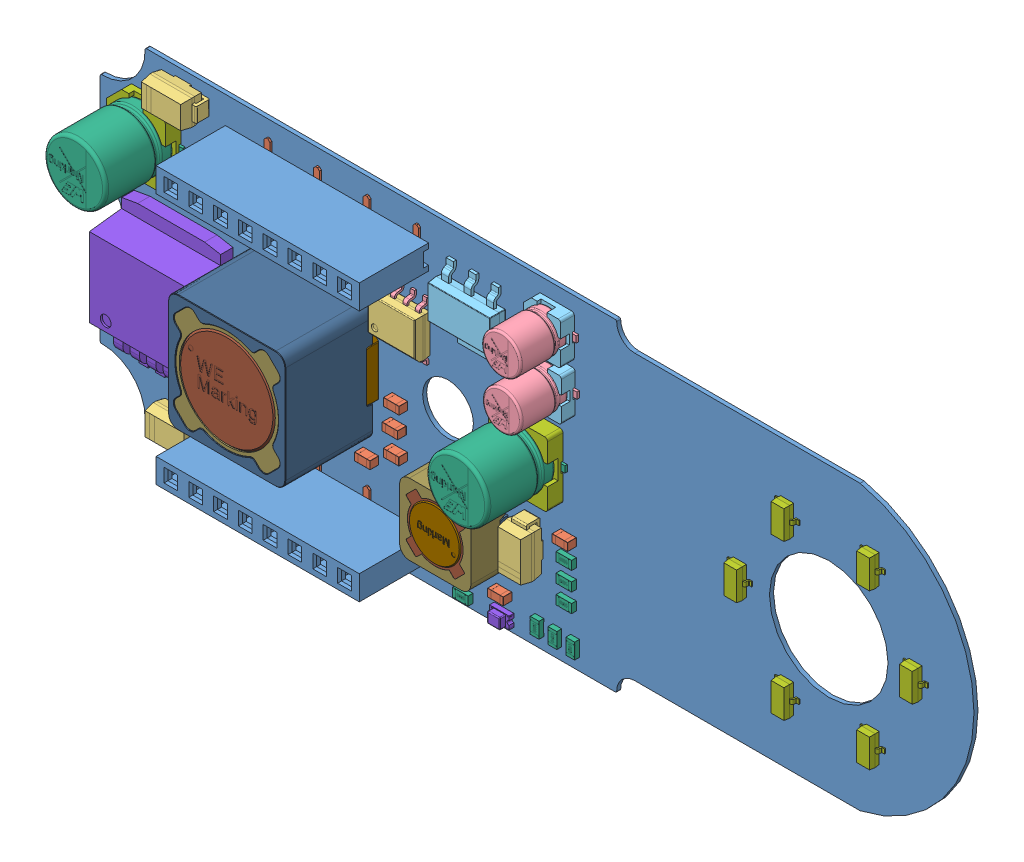
SolidWorks assembly magic_arm_1_PCB_18_9, configuration Default. Lengths in mm.
Overall size (89.5 33.05 10.11).
125 component instances, 33 part files, 0 mates.
Components (placement in the parent):
- Board-1: Board [Default] at (0 0 -0.4115) size (89.5 33.05 0.41)
- C13-1: C13 [Default] at origin size (1.6 0.8 0.9)
  - User_Library-CAPC1608X09-1: User_Library-CAPC1608X09 [Default] at (47.849 11.1761 0) x (1 0 0) z (0 0 1) size (1.6 0.8 0.9)
- IC1-1: IC1 [Default] at origin size (5 6.01 1.75)
  - User_Library-SOIC-8-1: User_Library-SOIC-8 [Default] at (31.4305 22.4028 0) x (1 0 0) z (0 -1 0) size (5 1.75 6.01)
    - User_Library-SOIC-8_SOIC-8_Body_1-1: User_Library-SOIC-8_SOIC-8_Body_1 [Default] at origin size (5 1.6 4)
    - User_Library-SOIC-8_SOIC-8_Pins_1-1: User_Library-SOIC-8_SOIC-8_Pins_1 [Default] at origin size (4.23 0.99 6.01)
- U1-1: U1 [Default] at origin size (6.5 6.96 1.68)
  - SW3DPS-SOT-223-DEFAULT-1: SW3DPS-SOT-223-DEFAULT [Default] at (38.2778 26.5681 0.78) x (1 0 0) z (0 -1 0) size (6.5 1.68 6.96)
- R7-1: R7 [Default] at origin size (1.6 0.9 0.5)
  - User_Library-R_0603-1: User_Library-R_0603 [Default] at (37.2595 0.889 0) size (1.6 0.9 0.5)
- R6-1: R6 [Default] at origin size (0.9 1.6 0.5)
  - User_Library-R_0603-1: User_Library-R_0603 [Default] at (48.514 1.9051 0) x (0 1 0) z (0 0 1) size (1.6 0.9 0.5)
- R5-1: R5 [Default] at origin size (0.9 1.6 0.5)
  - User_Library-R_0603-1: User_Library-R_0603 [Default] at (46.6902 1.9305 0) x (0 1 0) z (0 0 1) size (1.6 0.9 0.5)
- R4-1: R4 [Default] at origin size (0.9 1.6 0.5)
  - User_Library-R_0603-1: User_Library-R_0603 [Default] at (44.8665 1.9305 0) x (0 1 0) z (0 0 1) size (1.6 0.9 0.5)
- R3-1: R3 [Default] at origin size (1.6 0.9 0.5)
  - User_Library-R_0603-1: User_Library-R_0603 [Default] at (47.8491 5.5118 0) x (1 0 0) z (0 0 1) size (1.6 0.9 0.5)
- R2-1: R2 [Default] at origin size (1.6 0.9 0.5)
  - User_Library-R_0603-1: User_Library-R_0603 [Default] at (47.8491 7.4282 0) x (1 0 0) z (0 0 1) size (1.6 0.9 0.5)
- R1-1: R1 [Default] at origin size (1.6 0.9 0.5)
  - User_Library-R_0603-1: User_Library-R_0603 [Default] at (47.8491 9.3446 0) x (1 0 0) z (0 0 1) size (1.6 0.9 0.5)
- Q6-1: Q6 [Default] at origin size (2.5 3 1.1)
  - SW3DPS-SOT-23-DEFAULT-1: SW3DPS-SOT-23-DEFAULT [Default] at (65.4573 16.4985 0.508) x (0 1 0) z (1 0 0) size (3 1.1 2.5)
- Q5-1: Q5 [Default] at origin size (2.5 3 1.1)
  - SW3DPS-SOT-23-DEFAULT-1: SW3DPS-SOT-23-DEFAULT [Default] at (70.3073 8.4835 0.508) x (0 1 0) z (1 0 0) size (3 1.1 2.5)
- Q4-1: Q4 [Default] at origin size (2.5 3 1.1)
  - SW3DPS-SOT-23-DEFAULT-1: SW3DPS-SOT-23-DEFAULT [Default] at (79.0703 8.4835 0.508) x (0 1 0) z (1 0 0) size (3 1.1 2.5)
- Q3-1: Q3 [Default] at origin size (2.5 3 1.1)
  - SW3DPS-SOT-23-DEFAULT-1: SW3DPS-SOT-23-DEFAULT [Default] at (83.4573 16.4985 0.508) x (0 1 0) z (1 0 0) size (3 1.1 2.5)
- Q2-1: Q2 [Default] at origin size (2.5 3 1.1)
  - SW3DPS-SOT-23-DEFAULT-1: SW3DPS-SOT-23-DEFAULT [Default] at (79.0703 24.3585 0.508) x (0 1 0) z (1 0 0) size (3 1.1 2.5)
- Q1-1: Q1 [Default] at origin size (2.5 3 1.1)
  - SW3DPS-SOT-23-DEFAULT-1: SW3DPS-SOT-23-DEFAULT [Default] at (70.3073 24.3585 0.508) x (0 1 0) z (1 0 0) size (3 1.1 2.5)
- LED1-1: LED1 [Default] at origin size (2.02 1.25 1.1)
  - User_Library-led_0805-blue-1: User_Library-led_0805-blue [Default] at (41.2496 1.0414 0) x (-1 0 0) z (0 0 1) size (2.02 1.25 1.1)
- L1-1: L1 [Default] at origin size (12 12 9.66)
  - IndPDA_1210-1: IndPDA_1210 [Default] at (22.5299 16.4001 0.45) x (1 0 0) z (0 0 1) size (12 12 9.66)
    - Umspritzung12-12_1-1: Umspritzung12-12_1 [Default] at (0 0 0.94) x (1 0 0) z (0 0 -1) size (12 12 1.3)
    - 12x12-9mm-1: 12x12-9mm [Default] at (0 0 9.25) size (12 12 9)
    - Core_PD_12x12-9-1: Core_PD_12x12-9 [Default] at (0 0 4.75) size (9.85 9.85 9)
    - Glue-1: Glue [Default] at origin size (10.8 10.8 8.9)
    - Leadframe_bended-1: Leadframe_bended [Default] at origin size (11.55 12 3.98)
      - Leadframe-1: Leadframe [Default] at origin size (9.3 3.5 0.71)
      - Leadframe_2-1: Leadframe_2 [Default] at origin size (9.3 3.5 0.71)
      - PIN_1-1: PIN_1 [Default] at (-4.2957 4.2957 -5.8993) x (0.5 0.5 -0.707107) z (0.707107 -0.707107 0) size (2.61 2.72 1.6)
      - PIN_2-1: PIN_2 [Default] at (4.2957 4.2957 -5.8993) x (0.5 -0.5 0.707107) z (-0.707107 -0.707107 0) size (2.71 2.61 1.51)
      - PIN_3-1: PIN_3 [Default] at (4.2957 -4.2957 -5.8993) x (0.5 0.5 0.707107) z (-0.707107 0.707107 0) size (2.72 2.61 1.6)
      - PIN_4-1: PIN_4 [Default] at (-4.2957 -4.2957 -5.8993) x (0.5 -0.5 -0.707107) z (0.707107 0.707107 0) size (2.61 2.72 1.6)
- J2-1: J2 [Default] at origin size (20.82 4.05 7.5)
  - 61000813321-1: 61000813321 [Default] at (23.4999 3.5 3.95) x (1 0 0) z (0 0 1) size (20.82 4.05 7.5)
    - 6100081xx21-1: 6100081xx21 [Default] at origin size (20.82 2.5 7.1)
    - 6100xx1xx21_PIN-1: 6100xx1xx21_PIN [Default] at (-8.89 -0.725 -3.04) x (-1 0 0) z (0 0 -1) size (2 2.81 6.11)
    - 6100xx1xx21_PIN-2: 6100xx1xx21_PIN [Default] at (-6.35 0.725 -3.04) x (1 0 0) z (0 0 -1) size (2 2.81 6.11)
    - 6100xx1xx21_PIN-3: 6100xx1xx21_PIN [Default] at (-3.81 -0.725 -3.04) x (-1 0 0) z (0 0 -1) size (2 2.81 6.11)
    - 6100xx1xx21_PIN-4: 6100xx1xx21_PIN [Default] at (-1.27 0.725 -3.04) x (1 0 0) z (0 0 -1) size (2 2.81 6.11)
    - 6100xx1xx21_PIN-5: 6100xx1xx21_PIN [Default] at (1.27 -0.725 -3.04) x (-1 0 0) z (0 0 -1) size (2 2.81 6.11)
    - 6100xx1xx21_PIN-6: 6100xx1xx21_PIN [Default] at (3.81 0.725 -3.04) x (1 0 0) z (0 0 -1) size (2 2.81 6.11)
    - 6100xx1xx21_PIN-7: 6100xx1xx21_PIN [Default] at (6.35 -0.725 -3.04) x (-1 0 0) z (0 0 -1) size (2 2.81 6.11)
    - 6100xx1xx21_PIN-8: 6100xx1xx21_PIN [Default] at (8.89 0.725 -3.04) x (1 0 0) z (0 0 -1) size (2 2.81 6.11)
- J1-1: J1 [Default] at origin size (20.82 4.05 7.5)
  - 61000813321-1: 61000813321 [Default] at (23.4999 29.2999 3.95) x (1 0 0) z (0 0 1) size (20.82 4.05 7.5)
    - 6100081xx21-1: 6100081xx21 [Default] at origin size (20.82 2.5 7.1)
    - 6100xx1xx21_PIN-1: 6100xx1xx21_PIN [Default] at (-8.89 -0.725 -3.04) x (-1 0 0) z (0 0 -1) size (2 2.81 6.11)
    - 6100xx1xx21_PIN-2: 6100xx1xx21_PIN [Default] at (-6.35 0.725 -3.04) x (1 0 0) z (0 0 -1) size (2 2.81 6.11)
    - 6100xx1xx21_PIN-3: 6100xx1xx21_PIN [Default] at (-3.81 -0.725 -3.04) x (-1 0 0) z (0 0 -1) size (2 2.81 6.11)
    - 6100xx1xx21_PIN-4: 6100xx1xx21_PIN [Default] at (-1.27 0.725 -3.04) x (1 0 0) z (0 0 -1) size (2 2.81 6.11)
    - 6100xx1xx21_PIN-5: 6100xx1xx21_PIN [Default] at (1.27 -0.725 -3.04) x (-1 0 0) z (0 0 -1) size (2 2.81 6.11)
    - 6100xx1xx21_PIN-6: 6100xx1xx21_PIN [Default] at (3.81 0.725 -3.04) x (1 0 0) z (0 0 -1) size (2 2.81 6.11)
    - 6100xx1xx21_PIN-7: 6100xx1xx21_PIN [Default] at (6.35 -0.725 -3.04) x (-1 0 0) z (0 0 -1) size (2 2.81 6.11)
    - 6100xx1xx21_PIN-8: 6100xx1xx21_PIN [Default] at (8.89 0.725 -3.04) x (1 0 0) z (0 0 -1) size (2 2.81 6.11)
- DIO2-1: DIO2 [Default] at origin size (5.21 2.6 2.43)
  - User_Library-DO-214Aa_SMA-1: User_Library-DO-214Aa_SMA [Default] at (8.8561 1.9789 1.4) x (0 1 0) z (0 0 1) size (2.6 5.21 2.43)
- DIO1-1: DIO1 [Default] at origin size (5.21 2.6 2.43)
  - User_Library-DO-214Aa_SMA-1: User_Library-DO-214Aa_SMA [Default] at (8.5005 30.9603 1.4) x (0 1 0) z (0 0 1) size (2.6 5.21 2.43)
- C12-1: C12 [Default] at origin size (5 4.3 5.5)
  - 4x5.5x1-1: 4x5.5x1 [Default] at (46.4567 24.4348 0.1) x (0 -1 0) z (0 0 1) size (4.3 5 5.5)
    - capicitor_4x5.5x1-1: capicitor_4x5.5x1 [Default] at (0 0 0.5) x (0 -1 0) z (0 0 1) size (5 4 5.5)
    - Base___X2__03A6__X0__4Capacitor-1: Base___X2__03A6__X0__4Capacitor [Default] at origin size (4.3 4.3 1.46)
- C11-1: C11 [Default] at origin size (5 4.3 5.5)
  - 4x5.5x1-1: 4x5.5x1 [Default] at (46.3805 29.3878 0.1) x (0 -1 0) z (0 0 1) size (4.3 5 5.5)
    - capicitor_4x5.5x1-1: capicitor_4x5.5x1 [Default] at (0 0 0.5) x (0 -1 0) z (0 0 1) size (5 4 5.5)
    - Base___X2__03A6__X0__4Capacitor-1: Base___X2__03A6__X0__4Capacitor [Default] at origin size (4.3 4.3 1.46)
- C10-1: C10 [Default] at origin size (7.3 6.6 7.75)
  - 6.3x7.7x2.2-1: 6.3x7.7x2.2 [Default] at (44.0689 17.2719 0.1) x (0 -1 0) z (0 0 1) size (6.6 7.3 7.75)
    - capicitor_6.3x7.7x2.2-1: capicitor_6.3x7.7x2.2 [Default] at (0 0 0.5) x (0 -1 0) z (0 0 1) size (7.3 6.3 7.75)
    - Base___X2__03A6__X0__6_3Capacitor-1: Base___X2__03A6__X0__6_3Capacitor [Default] at origin size (6.6 6.6 1.6)
- C9-1: C9 [Default] at origin size (1.6 0.8 0.9)
  - User_Library-CAPC1608X09-1: User_Library-CAPC1608X09 [Default] at (30.4292 12.3699 0) size (1.6 0.8 0.9)
- C8-1: C8 [Default] at origin size (1.6 0.8 0.9)
  - User_Library-CAPC1608X09-1: User_Library-CAPC1608X09 [Default] at (30.5562 10.1093 0) x (1 0 0) z (0 0 1) size (1.6 0.8 0.9)
- C7-1: C7 [Default] at origin size (7.3 6.6 7.75)
  - 6.3x7.7x2.2-1: 6.3x7.7x2.2 [Default] at (4.9275 25.8571 0.1) x (0 -1 0) z (0 0 1) size (6.6 7.3 7.75)
    - capicitor_6.3x7.7x2.2-1: capicitor_6.3x7.7x2.2 [Default] at (0 0 0.5) x (0 -1 0) z (0 0 1) size (7.3 6.3 7.75)
    - Base___X2__03A6__X0__6_3Capacitor-1: Base___X2__03A6__X0__6_3Capacitor [Default] at origin size (6.6 6.6 1.6)
- C6-1: C6 [Default] at origin size (1.6 0.8 0.9)
  - User_Library-CAPC1608X09-1: User_Library-CAPC1608X09 [Default] at (23.0378 8.2805 0) size (1.6 0.8 0.9)
- C5-1: C5 [Default] at origin size (1.6 0.8 0.9)
  - User_Library-CAPC1608X09-1: User_Library-CAPC1608X09 [Default] at (17.5514 8.2805 0) size (1.6 0.8 0.9)
- C4-1: C4 [Default] at origin size (1.6 0.8 0.9)
  - User_Library-CAPC1608X09-1: User_Library-CAPC1608X09 [Default] at (30.5816 14.6305 0) size (1.6 0.8 0.9)
- C3-1: C3 [Default] at origin size (1.6 0.8 0.9)
  - User_Library-CAPC1608X09-1: User_Library-CAPC1608X09 [Default] at (37.211 2.6923 0) x (-1 0 0) z (0 0 1) size (1.6 0.8 0.9)
- C2-1: C2 [Default] at origin size (1.6 0.8 0.9)
  - User_Library-CAPC1608X09-1: User_Library-CAPC1608X09 [Default] at (27.6098 8.3059 0) size (1.6 0.8 0.9)
- C1-1: C1 [Default] at origin size (1.6 0.8 0.9)
  - User_Library-CAPC1608X09-1: User_Library-CAPC1608X09 [Default] at (41.2496 3.0479 0) x (-1 0 0) z (0 0 1) size (1.6 0.8 0.9)
- 1-1: 1 [Default] at origin size (10.28 14.64 4.68)
  - 1144353280-1: 1144353280 [Default] at (8.4028 8.7489 0) x (-1 0 0) z (0 0 1) size (10.28 14.64 4.68)
- DIO3-1: DIO3 [Default] at origin size (2.6 5.21 2.43)
  - User_Library-DO-214Aa_SMA-1: User_Library-DO-214Aa_SMA [Default] at (44.1729 8.9069 1.4) x (-1 0 0) z (0 0 1) size (2.6 5.21 2.43)
- L2-1: L2 [Default] at origin size (7.3 7.3 4)
  - IndPDA_7345-1: IndPDA_7345 [Default] at (38.1509 8.6107 0.3) size (7.3 7.3 4)
    - Ferrite_5.3x3.6-1: Ferrite_5.3x3.6 [Default] at (0 0 0.15) size (5.3 5.3 3.6)
    - Umspritzung_1-1: Umspritzung_1 [Default] at (0 0 0.66) x (1 0 0) z (0 0 -1) size (7.15 7.15 0.9)
    - Glue_2-1: Glue_2 [Default] at origin size (5.95 5.95 2.94)
    - Ferrite-Ring7.3x3.5x5.7-1: Ferrite-Ring7.3x3.5x5.7 [Default] at (0 0 0.16) size (7.3 7.3 3.5)
    - Leadframe-1: Leadframe [Default] at origin size (7.19 7.19 3.21)
      - Leadframe_3-1: Leadframe_3 [Default] at origin size (5.16 2.58 0.5)
      - Leadframe_4-1: Leadframe_4 [Default] at origin size (5.16 2.58 0.5)
      - contact-1: contact [Default] at (-2.3342 -2.3342 -3.3) x (0.5 -0.5 0.707107) z (0.707107 0.707107 0) size (2.16 2.16 0.93)
      - contact-2: contact [Default] at (2.3342 -2.3342 -3.3) x (0.5 0.5 0.707107) z (-0.707107 0.707107 0) size (2.16 2.16 0.93)
      - contact-3: contact [Default] at (2.3342 2.3342 -3.3) x (-0.5 0.5 0.707107) z (-0.707107 -0.707107 0) size (2.16 2.16 0.93)
      - contact-4: contact [Default] at (-2.3342 2.3342 -3.3) x (-0.5 -0.5 0.707107) z (0.707107 -0.707107 0) size (2.16 2.16 0.93)
